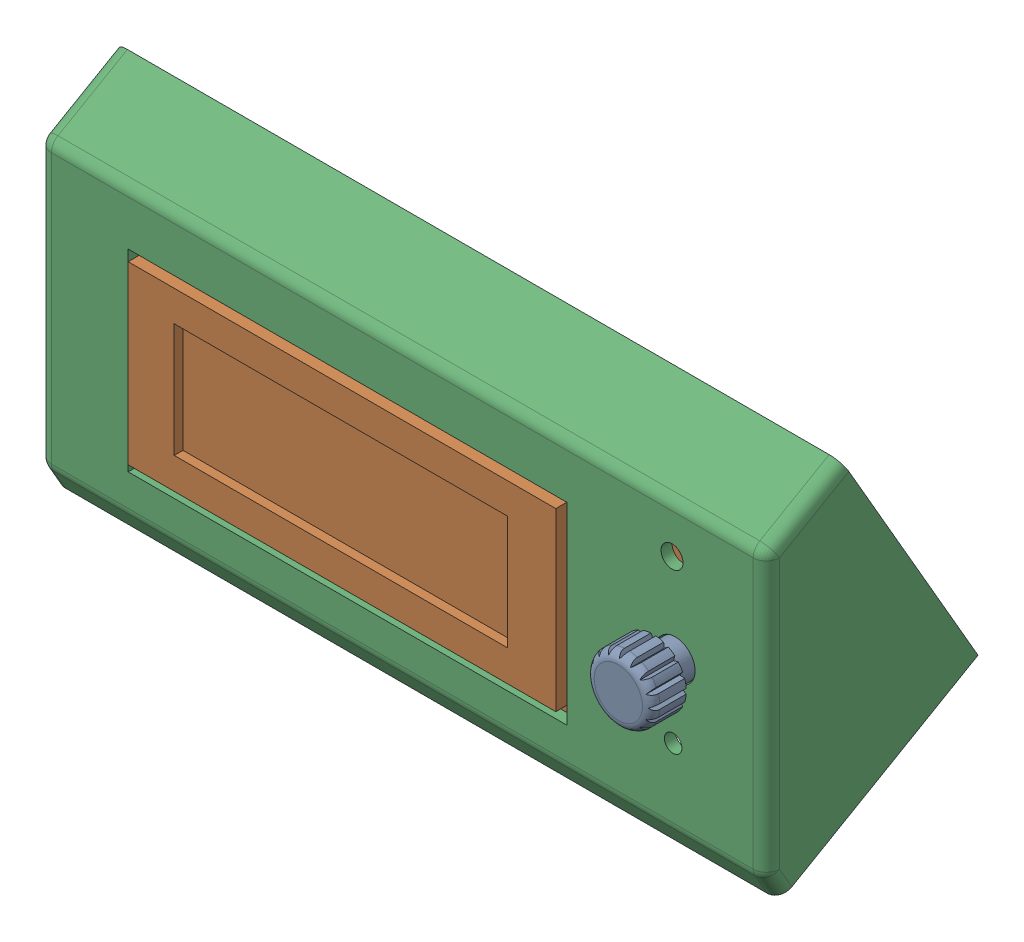
SolidWorks assembly screen stand ass_Default, configuration Default. Lengths in mm.
Overall size (166 79.58 61.26).
3 component instances, 3 part files, 0 mates.
Components (placement in the parent):
- button-1: button [Default] at (137.25 25 16.5) size (15.22 15.22 13.5)
- screen_Default-1: screen_Default [Default] at origin size (150.5 63.5 29.5)
- screen stand-1: screen stand [Default] at (75 -14.3 13) size (166 79.58 48.26)
